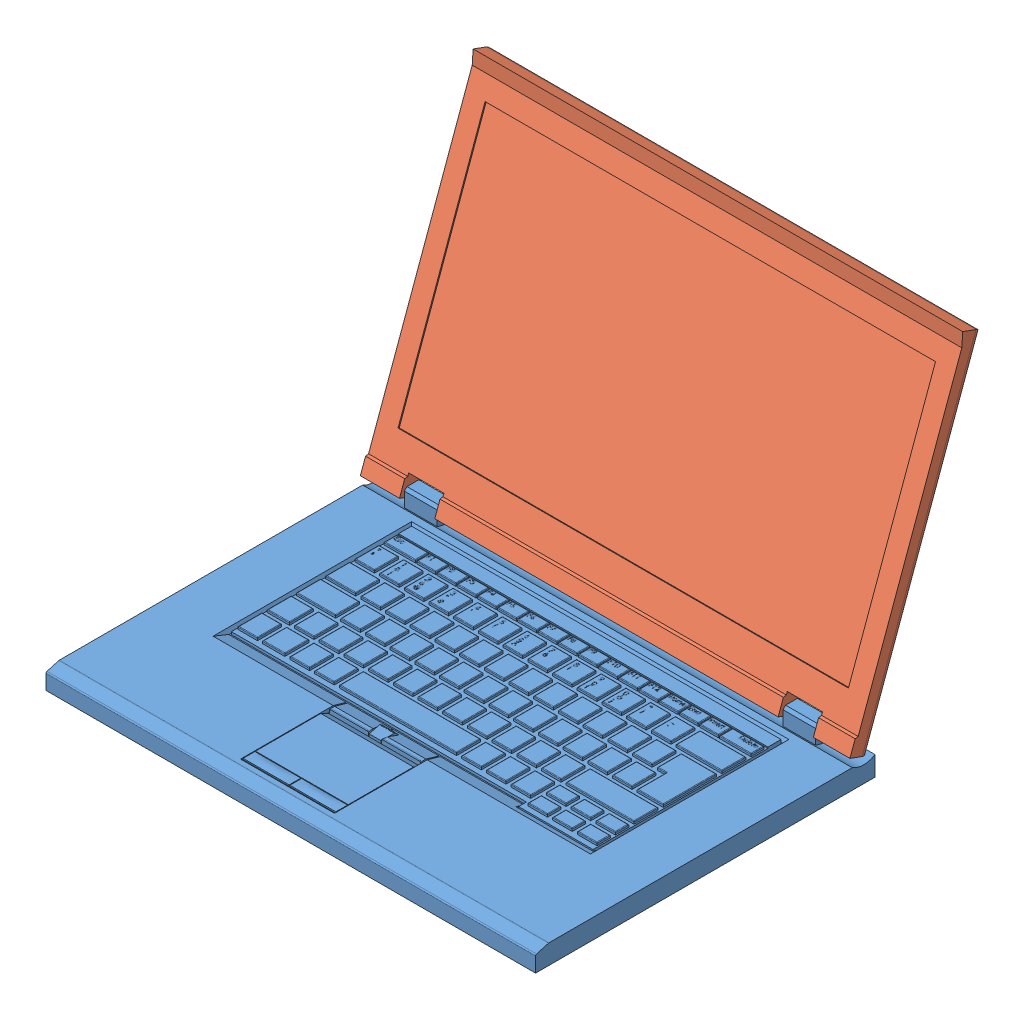
SolidWorks assembly lenovo thinkstation W530, configuration Default. Lengths in mm.
Overall size (376 260.96 343.08).
2 component instances, 2 part files, 3 mates.
Components (placement in the parent):
- lenovo-1: lenovo [Default] at (-3.9632 154.505 414.3508) size (375 27 260)
- screen-1: screen [Default] at (-4.9632 170.4124 158.4831) x (1 0 0) z (0 0.34202 0.939693) size (375 255 15.87)
Mates (geometry in assembly coordinates):
- Concentric1: concentric anti-aligned: cylinder of lenovo-1 through (56.0368 177.505 163.3508) axis (-1 0 0) radius 2; cylinder of screen-1 through (12.0368 177.505 163.3508) axis (1 0 0) radius 2
- Distance1: distance = 1 mm anti-aligned: plane of screen-1 through (25.0368 165.2821 144.3877) normal (1 0 0); plane of lenovo-1 through (26.0368 -499845.495 156.8508) normal (-1 0 0)
- LimitAngle1: limit planar angle = 1.22173 rad aligned: plane of screen-1 through (370.0368 184.2555 167.2789) normal (0 0.34202 0.939693); plane of lenovo-1 through (-3.9632 169.505 414.3508) normal (0 1 0)
